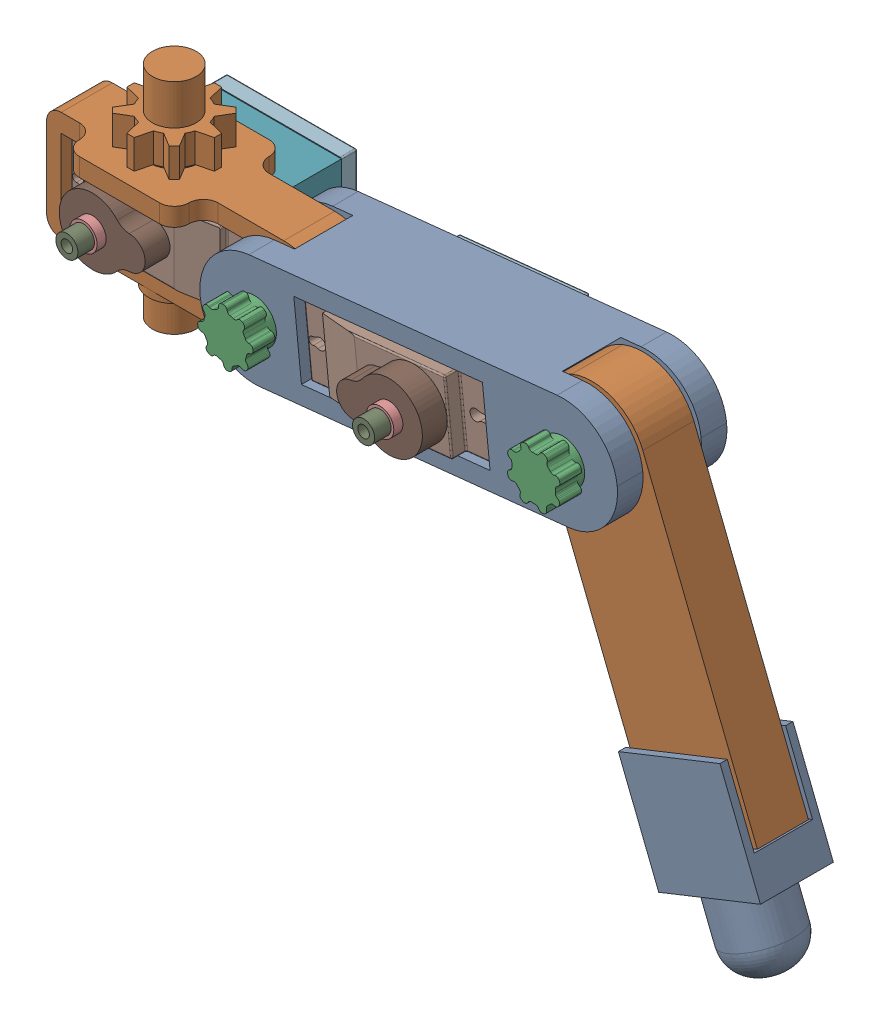
SolidWorks assembly Leg Assembly V1, configuration Default. Lengths in mm.
Overall size (130.88 88.19 39.01).
8 component instances, 6 part files, 22 mates.
Components (placement in the parent):
- Leg-Medial-1: Leg-Medial [Default] at (1.0858 19.7391 24.1073) x (0.994508 0.104658 0) z (0 0 1) size (73.03 19.05 19.05)
- Leg-Distal-1: Leg-Distal [Default] at (31.3994 1.4124 24.1073) x (0.369433 -0.929257 0) z (0 0 1) size (63.5 19.05 8.89)
- Leg-MidJoint-Pin-1: Leg-MidJoint-Pin [Default] at (23.1888 22.0651 36.1723) x (0.369433 -0.929257 0) z (0 0 1) size (9.65 9.65 27.94)
- SERVO MG92B-1: SERVO MG92B [Predeterminado] at (-6.5572 18.8745 9.9273) x (0.994508 0.104658 0) z (0.104658 -0.994508 0) size (31.69 33.93 12.06)
- Leg-Foot-1: Leg-Foot [Default] at (29.6798 -20.0449 24.1073) x (0.929257 0.369433 0) z (0 0 1) size (19.05 31.75 12.7)
- Leg-Proximal-2: Leg-Proximal [Default] at (-46.3648 16.4162 24.1073) size (50.8 38.1 19.05)
- Leg-MidJoint-Pin-2: Leg-MidJoint-Pin [Default] at (-30.4898 16.4162 36.1723) x (0.994508 0.104658 0) z (0 0 1) size (9.65 9.65 27.94)
- SERVO MG92B-2: SERVO MG92B [Predeterminado] at (-52.7148 16.4762 4.8473) x (-1 0 0) z (0 1 0) size (31.69 33.93 12.06)
Mates (geometry in assembly coordinates):
- Coincident1: coincident anti-aligned: plane of Leg-Distal-1 through (26.2529 21.2332 19.6623) normal (-0.369433 0.929257 0); plane of Leg-MidJoint-Pin-1 through (26.2529 21.2332 10.7723) normal (0.369433 -0.929257 0)
- Concentric1: concentric aligned: cylinder of Leg-Distal-1 through (23.1888 22.0651 19.6623) axis (0 0 1) radius 3.175; cylinder of Leg-MidJoint-Pin-1 through (23.1888 22.0651 10.7723) axis (0 0 1) radius 3.175
- Coincident2: coincident anti-aligned: plane of Leg-Medial-1 through (1.0858 19.7391 33.6323) normal (0 0 1); plane of Leg-MidJoint-Pin-1 through (23.1888 22.0651 33.6323) normal (0 0 -1)
- Concentric2: concentric aligned: cylinder of Leg-Medial-1 through (23.1888 22.0651 14.5823) axis (0 0 1) radius 3.175; cylinder of Leg-MidJoint-Pin-1 through (23.1888 22.0651 10.7723) axis (0 0 1) radius 3.175
- Width1: width anti-aligned: plane of Leg-Distal-1 through (31.3994 1.4124 28.5523) normal (0 0 1); plane of Leg-Distal-1 through (31.3994 1.4124 19.6623) normal (0 0 -1); plane of Leg-Medial-1 through (23.1888 22.0651 29.1873) normal (0 0 -1); plane of Leg-Medial-1 through (23.1888 22.0651 19.0273) normal (0 0 1)
- Width2: width aligned: plane of SERVO MG92B-1; plane of SERVO MG92B-1; plane of Leg-Proximal-1; plane of Leg-Proximal-1
- Coincident3: coincident anti-aligned: plane of Leg-Proximal-1 through (1.2602 16.4162 33.6323) normal (0 0 1); plane of SERVO MG92B-1 through (4.2387 10.3262 33.6323) normal (0 0 -1)
- Coincident4: coincident anti-aligned: plane of Leg-Proximal-1; plane of SERVO MG92B-1
- Width4: width anti-aligned: plane of SERVO MG92B-1 through (-22.3152 17.2162 9.9273) normal (-0.994508 -0.104658 0); plane of SERVO MG92B-1 through (9.2008 20.5328 9.9273) normal (0.994508 0.104658 0); plane of Leg-Medial-1 through (-22.3182 10.8911 33.6323) normal (0.994508 0.104658 0); plane of Leg-Medial-1 through (10.5204 14.3469 33.6323) normal (-0.994508 -0.104658 0)
- Width5: width anti-aligned: plane of SERVO MG92B-1 through (-7.1851 24.8415 9.9273) normal (-0.104658 0.994508 0); plane of SERVO MG92B-1 through (-5.9418 13.0267 9.9273) normal (0.104658 -0.994508 0); plane of Leg-Medial-1 through (-23.6474 23.5214 33.6323) normal (0.104658 -0.994508 0); plane of Leg-Medial-1 through (-22.3182 10.8911 33.6323) normal (-0.104658 0.994508 0)
- Coincident5: coincident anti-aligned: plane of Leg-Medial-1 through (1.0858 19.7391 30.4573) normal (0 0 1); plane of SERVO MG92B-1 through (-22.9463 23.213 30.4573) normal (0 0 -1)
- Concentric3: concentric aligned: cylinder of Leg-Distal-1 through (45.5037 -20.314 15.8523) axis (0 0 1) radius 1.5875; circle of Leg-Foot-1
- Concentric4: concentric aligned: cylinder of Leg-Distal-1 through (36.0624 -24.0675 15.8523) axis (0 0 1) radius 1.5875; circle of Leg-Foot-1
- Width6: width anti-aligned: plane of Leg-Foot-1 through (34.5048 -8.9345 19.0273) normal (0 0 1); plane of Leg-Foot-1 through (34.5048 -8.9345 29.1873) normal (0 0 -1); plane of Leg-Distal-1 through (31.3994 1.4124 19.6623) normal (0 0 -1); plane of Leg-Distal-1 through (31.3994 1.4124 28.5523) normal (0 0 1)
- Width7: width anti-aligned: plane of Leg-Proximal-2 through (-46.3648 16.4162 28.5523) normal (0 0 1); plane of Leg-Proximal-2 through (-46.3648 16.4162 19.6623) normal (0 0 -1); plane of Leg-Medial-1 through (-30.4898 16.4162 29.1873) normal (0 0 -1); plane of Leg-Medial-1 through (-30.4898 16.4162 19.0273) normal (0 0 1)
- Concentric5: concentric aligned: cylinder of Leg-Medial-1 through (-30.4898 16.4162 14.5823) axis (0 0 1) radius 3.175; cylinder of Leg-Proximal-2 through (-30.4898 16.4162 19.6623) axis (0 0 1) radius 3.302
- Concentric6: concentric aligned: cylinder of Leg-Proximal-2 through (-30.4898 16.4162 19.6623) axis (0 0 1) radius 3.302; cylinder of Leg-MidJoint-Pin-2 through (-30.4898 16.4162 10.7723) axis (0 0 1) radius 3.175
- Coincident6: coincident anti-aligned: plane of Leg-Medial-1 through (-28.8611 19.1416 14.5823) normal (-0.994508 -0.104658 0); plane of Leg-MidJoint-Pin-2 through (-28.8611 19.1416 10.7723) normal (0.994508 0.104658 0)
- Coincident7: coincident anti-aligned: plane of Leg-Medial-1 through (1.0858 19.7391 33.6323) normal (0 0 1); plane of Leg-MidJoint-Pin-2 through (-30.4898 16.4162 33.6323) normal (0 0 -1)
- Width8: width aligned: plane of SERVO MG92B-2 through (-52.7148 22.3562 4.8473) normal (0 1 0); plane of SERVO MG92B-2 through (-52.7148 10.4762 4.8473) normal (0 -1 0); plane of Leg-Proximal-2 through (-69.2248 10.0662 28.5523) normal (0 1 0); plane of Leg-Proximal-2 through (-69.2248 22.7662 28.5523) normal (0 -1 0)
- Width9: width anti-aligned: plane of SERVO MG92B-2 through (-68.5598 16.4762 4.8473) normal (-1 0 0); plane of SERVO MG92B-2 through (-36.8698 16.4762 4.8473) normal (1 0 0); plane of Leg-Proximal-2 through (-69.2248 10.0662 28.5523) normal (1 0 0); plane of Leg-Proximal-2 through (-36.2048 10.0662 28.5523) normal (-1 0 0)
- Coincident8: coincident anti-aligned: plane of Leg-Proximal-2 through (-46.3648 16.4162 25.3773) normal (0 0 1); plane of SERVO MG92B-2 through (-68.5598 22.5062 25.3773) normal (0 0 -1)
